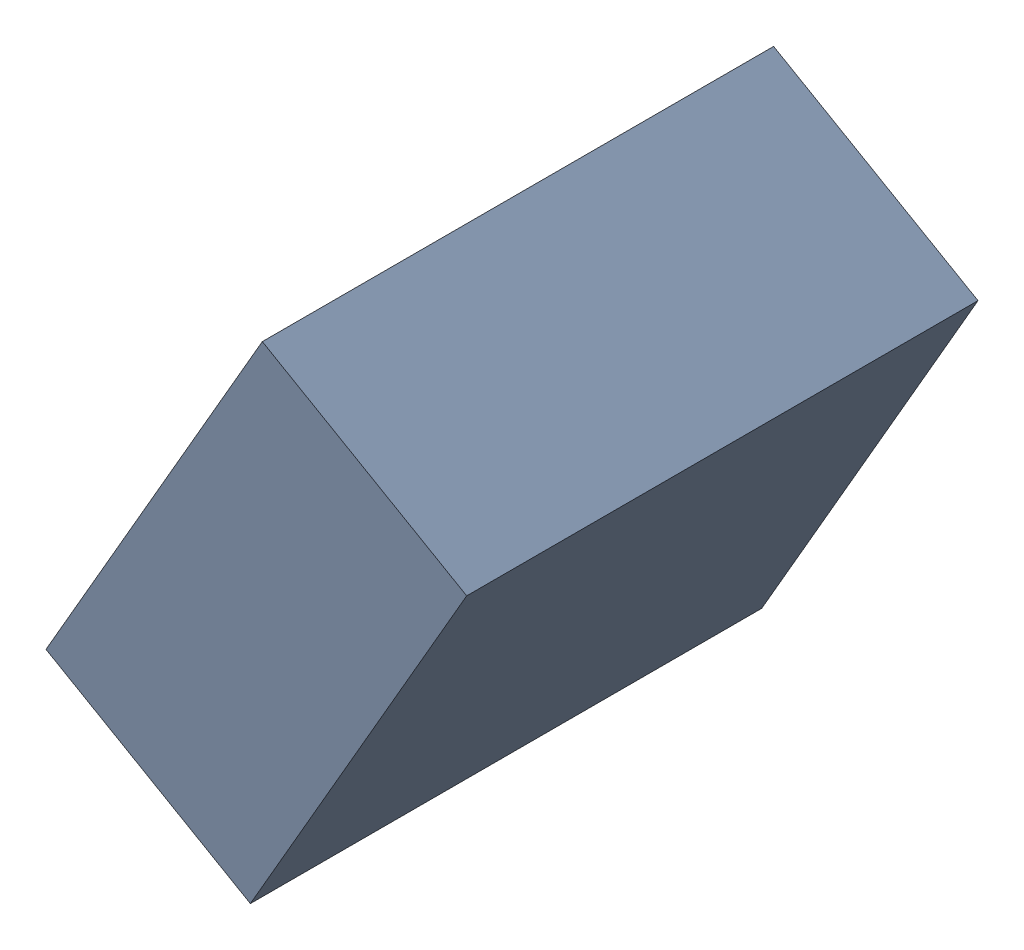
SolidWorks assembly C28_TDA6, configuration Standard. Lengths in mm.
Overall size (1.07 1.25 1.3).
2 component instances, 1 part files, 0 mates.
Components (placement in the parent):
- 885543328-1: 885543328 [Standard] at (-48.5577 30.2879 0) size (1.07 1.25 1.3)
  - Extruded_26-1: Extruded_26 [Standard] at origin size (1.07 1.25 1.3)
